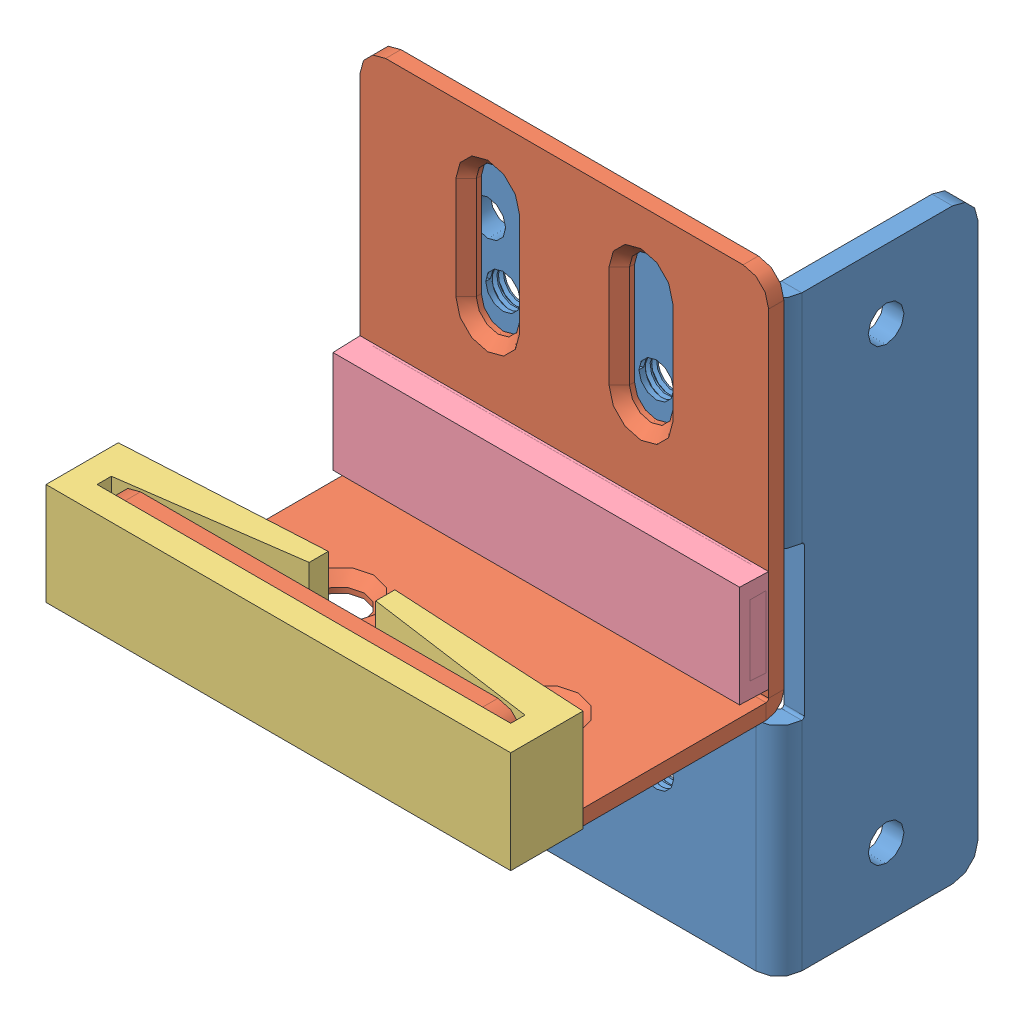
SolidWorks assembly B40-5B(Default)-, configuration Default. Lengths in mm.
Overall size (91 121.5 98).
4 component instances, 4 part files, 0 mates.
Components (placement in the parent):
- A-0027387(Default)--1: A-0027387(Default)- [Default] at (0 -57.5 -35) x (-1 0 0) z (0 0 -1) size (74 115 39.19)
- A-0027428(Default)--1: A-0027428(Default)- [Default] at (5 -10.5 58) x (-1 0 0) z (0 0 -1) size (80 74.5 54)
- G2305--1: G2305- [Default] at (-35 4.5 58) size (91 20 16.3)
- G2307--1: G2307- [Default] at (-35 4.5 7) size (80 19.97 5.5)
